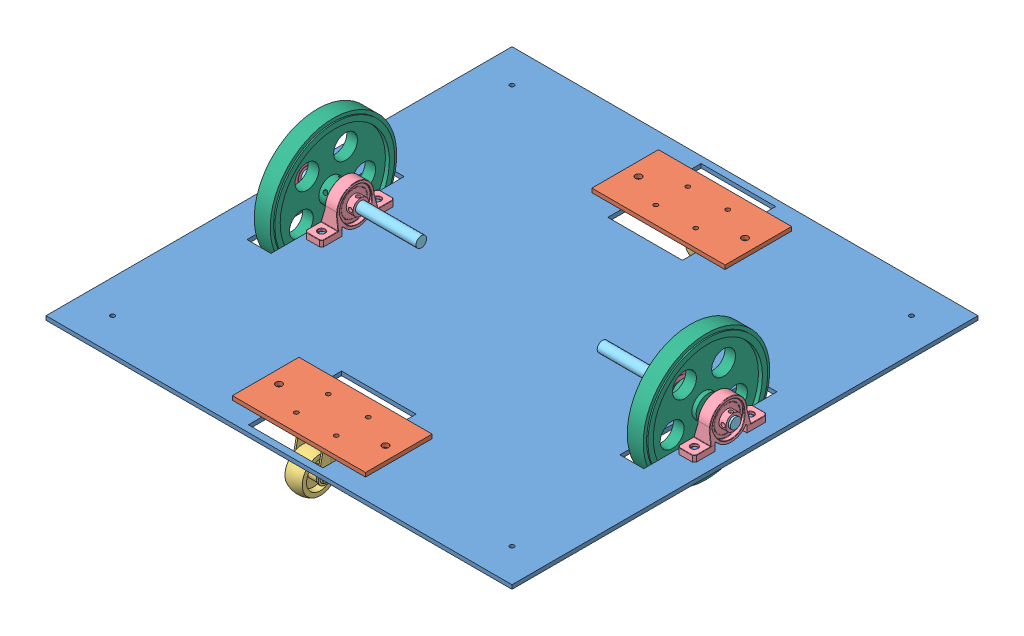
SolidWorks assembly main, configuration Default. Lengths in mm.
Overall size (350 127.26 350).
13 component instances, 6 part files, 34 mates.
Components (placement in the parent):
- Đế-1: Đế [Default] at origin size (350 3 350)
- Đế bánh xe đa hướng-2: Đế bánh xe đa hướng [Default] at (0 3 135) size (100 3 50)
- Đế bánh xe đa hướng-3: Đế bánh xe đa hướng [Default] at (0 3 -135) size (100 3 50)
- Caster-swivel-40mm_assembly.step-1: Caster-swivel-40mm_assembly.step [Default] at (0 -22 150.5) x (1 0 0) z (0 1 0) size (38 46.5 40)
- Caster-swivel-40mm_assembly.step-2: Caster-swivel-40mm_assembly.step [Default] at (0 -22 -150.5) x (-1 0 0) z (0 1 0) size (38 46.5 40)
- 8mm İç Çap - Rulmanlı Yatak-1: 8mm İç Çap - Rulmanlı Yatak [Varsayılan] at (-158 2.5 0) x (0 0 -1) z (1 0 0) size (55 28.5 15.02)
- 8mm İç Çap - Rulmanlı Yatak-2: 8mm İç Çap - Rulmanlı Yatak [Varsayılan] at (-122 2.5 0) x (0 0 1) z (-1 0 0) size (55 28.5 15.02)
- 8mm İç Çap - Rulmanlı Yatak-3: 8mm İç Çap - Rulmanlı Yatak [Varsayılan] at (122 2.5 0) x (0 0 -1) z (1 0 0) size (55 28.5 15.02)
- 8mm İç Çap - Rulmanlı Yatak-5: 8mm İç Çap - Rulmanlı Yatak [Varsayılan] at (158 2.5 0) x (0 0 1) z (-1 0 0) size (55 28.5 15.02)
- trục bánh xe-1: trục bánh xe [Default] at (-118.1191 17 0) x (1 0 0) z (0 -0.133394 0.991063) size (100 8 8)
- 95mm phi 8 99g-1: 95mm phi 8 99g [Default] at (-140.0943 17 0) x (0 -0.443129 -0.896458) z (1 0 0) size (95 95 19.2)
- trục bánh xe-3: trục bánh xe [Default] at (118 17 0) x (1 0 0) z (0 0.875419 0.483366) size (100 8 8)
- 95mm phi 8 99g-2: 95mm phi 8 99g [Default] at (140.0847 17 0) x (0 0.948818 -0.315822) z (-1 0 0) size (95 95 19.2)
Mates (geometry in assembly coordinates):
- Concentric5: concentric aligned: cylinder of Tấm đế bánh xe đa hướng-2 through (-15 3 123) axis (0 1 0) radius 1.6; cylinder of Caster-swivel-40mm_assembly.step-1 through (-15 3 123) axis (0 1 0) radius 2
- Concentric6: concentric aligned: cylinder of Tấm đế bánh xe đa hướng-2 through (15 3 123) axis (0 1 0) radius 1.6; cylinder of Caster-swivel-40mm_assembly.step-1 through (15 3 123) axis (0 1 0) radius 2
- Concentric7: concentric aligned: cylinder of Tấm đế bánh xe đa hướng-2 through (15 3 147) axis (0 1 0) radius 1.6; cylinder of Caster-swivel-40mm_assembly.step-1 through (15 3 147) axis (0 1 0) radius 2
- Concentric8: concentric aligned: cylinder of Tấm đế bánh xe đa hướng-2 through (-15 3 147) axis (0 1 0) radius 1.6; cylinder of Caster-swivel-40mm_assembly.step-1 through (-15 3 147) axis (0 1 0) radius 2
- Coincident1: coincident anti-aligned: plane of Tấm đế bánh xe đa hướng-2 through (0 3 135) normal (0 -1 0); plane of Caster-swivel-40mm_assembly.step-1 through (0 3 135) normal (0 1 0)
- Concentric9: concentric aligned: cylinder of Tấm đế bánh xe đa hướng-3 through (-15 3 -147) axis (0 1 0) radius 1.6; cylinder of Caster-swivel-40mm_assembly.step-2 through (-15 3 -147) axis (0 1 0) radius 2
- Concentric10: concentric aligned: cylinder of Tấm đế bánh xe đa hướng-3 through (15 3 -147) axis (0 1 0) radius 1.6; cylinder of Caster-swivel-40mm_assembly.step-2 through (15 3 -147) axis (0 1 0) radius 2
- Concentric11: concentric aligned: cylinder of Tấm đế bánh xe đa hướng-3 through (-15 3 -123) axis (0 1 0) radius 1.6; cylinder of Caster-swivel-40mm_assembly.step-2 through (-15 3 -123) axis (0 1 0) radius 2
- Concentric12: concentric aligned: cylinder of Tấm đế bánh xe đa hướng-3 through (15 3 -123) axis (0 1 0) radius 1.6; cylinder of Caster-swivel-40mm_assembly.step-2 through (15 3 -123) axis (0 1 0) radius 2
- Coincident2: coincident anti-aligned: plane of Tấm đế bánh xe đa hướng-3 through (0 3 -135) normal (0 -1 0); plane of Caster-swivel-40mm_assembly.step-2 through (0 3 -135) normal (0 1 0)
- Concentric14: concentric aligned: cylinder of Đế New2-1 through (-40 0 -135) axis (0 1 0) radius 2.5; cylinder of Tấm đế bánh xe đa hướng-3 through (-40 3 -135) axis (0 1 0) radius 2.5
- Concentric15: concentric aligned: cylinder of Đế New2-1 through (40 0 -135) axis (0 1 0) radius 2.5; cylinder of Tấm đế bánh xe đa hướng-3 through (40 3 -135) axis (0 1 0) radius 2.5
- Coincident3: coincident anti-aligned: plane of Đế New2-1 through (0 3 0) normal (0 1 0); plane of Tấm đế bánh xe đa hướng-3 through (0 3 -135) normal (0 -1 0)
- Concentric16: concentric aligned: cylinder of Đế New2-1 through (-40 0 135) axis (0 1 0) radius 2.5; cylinder of Tấm đế bánh xe đa hướng-2 through (-40 3 135) axis (0 1 0) radius 2.5
- Concentric17: concentric aligned: cylinder of Đế New2-1 through (40 0 135) axis (0 1 0) radius 2.5; cylinder of Tấm đế bánh xe đa hướng-2 through (40 3 135) axis (0 1 0) radius 2.5
- Coincident4: coincident anti-aligned: plane of Đế New2-1 through (0 3 0) normal (0 1 0); plane of Tấm đế bánh xe đa hướng-2 through (0 3 135) normal (0 -1 0)
- Concentric18: concentric anti-aligned: cylinder of Đế New2-1 through (-158 0 -21) axis (0 1 0) radius 2.5; cylinder of 8mm İç Çap - Rulmanlı Yatak-1 through (-158 7.5 -21) axis (0 -1 0) radius 2.5
- Concentric19: concentric anti-aligned: cylinder of Đế New2-1 through (-158 0 21) axis (0 1 0) radius 2.5; cylinder of 8mm İç Çap - Rulmanlı Yatak-1 through (-158 7.5 21) axis (0 -1 0) radius 2.5
- Coincident5: coincident anti-aligned: plane of Đế New2-1 through (0 3 0) normal (0 1 0); plane of 8mm İç Çap - Rulmanlı Yatak-1 through (-159.25 3 0) normal (0 -1 0)
- Concentric20: concentric anti-aligned: cylinder of Đế New2-1 through (-122 0 -21) axis (0 1 0) radius 2.5; cylinder of 8mm İç Çap - Rulmanlı Yatak-2 through (-122 7.5 -21) axis (0 -1 0) radius 2.5
- Concentric21: concentric anti-aligned: cylinder of Đế New2-1 through (-122 0 21) axis (0 1 0) radius 2.5; cylinder of 8mm İç Çap - Rulmanlı Yatak-2 through (-122 7.5 21) axis (0 -1 0) radius 2.5
- Coincident6: coincident anti-aligned: plane of Đế New2-1 through (0 3 0) normal (0 1 0); plane of 8mm İç Çap - Rulmanlı Yatak-2 through (-120.75 3 0) normal (0 -1 0)
- Concentric22: concentric anti-aligned: cylinder of Đế New2-1 through (122 0 -21) axis (0 1 0) radius 2.5; cylinder of 8mm İç Çap - Rulmanlı Yatak-3 through (122 7.5 -21) axis (0 -1 0) radius 2.5
- Concentric23: concentric anti-aligned: cylinder of Đế New2-1 through (122 0 21) axis (0 1 0) radius 2.5; cylinder of 8mm İç Çap - Rulmanlı Yatak-3 through (122 7.5 21) axis (0 -1 0) radius 2.5
- Coincident7: coincident anti-aligned: plane of Đế New2-1 through (0 3 0) normal (0 1 0); plane of 8mm İç Çap - Rulmanlı Yatak-3 through (120.75 3 0) normal (0 -1 0)
- Concentric24: concentric anti-aligned: cylinder of Đế New2-1 through (158 0 -21) axis (0 1 0) radius 2.5; cylinder of 8mm İç Çap - Rulmanlı Yatak-5 through (158 7.5 -21) axis (0 -1 0) radius 2.5
- Concentric25: concentric anti-aligned: cylinder of Đế New2-1 through (158 0 21) axis (0 1 0) radius 2.5; cylinder of 8mm İç Çap - Rulmanlı Yatak-5 through (158 7.5 21) axis (0 -1 0) radius 2.5
- Coincident8: coincident anti-aligned: plane of Đế New2-1 through (0 3 0) normal (0 1 0); plane of 8mm İç Çap - Rulmanlı Yatak-5 through (159.25 3 0) normal (0 -1 0)
- Concentric26: concentric aligned: cylinder of 8mm İç Çap - Rulmanlı Yatak-1 through (-166.5 17 0) axis (1 0 0) radius 4; cylinder of trục bánh xe-1 through (-68.1191 17 0) axis (1 0 0) radius 4
- Concentric27: concentric anti-aligned: cylinder of 8mm İç Çap - Rulmanlı Yatak-2 through (-113.5 17 0) axis (-1 0 0) radius 4; cylinder of trục bánh xe-1 through (-68.1191 17 0) axis (1 0 0) radius 4
- Concentric28: concentric aligned: cylinder of trục bánh xe-1 through (-68.1191 17 0) axis (1 0 0) radius 4; cylinder of 95mm phi 8 99g-1 through (-147.2943 17 0) axis (1 0 0) radius 4
- Concentric32: concentric anti-aligned: cylinder of 8mm İç Çap - Rulmanlı Yatak-5 through (166.5 17 0) axis (-1 0 0) radius 4; cylinder of trục bánh xe-3 through (168 17 0) axis (1 0 0) radius 4
- Concentric33: concentric aligned: cylinder of 8mm İç Çap - Rulmanlı Yatak-3 through (113.5 17 0) axis (1 0 0) radius 4; cylinder of trục bánh xe-3 through (168 17 0) axis (1 0 0) radius 4
- Concentric35: concentric anti-aligned: cylinder of trục bánh xe-3 through (168 17 0) axis (1 0 0) radius 4; cylinder of 95mm phi 8 99g-2 through (147.2847 17 0) axis (-1 0 0) radius 4
